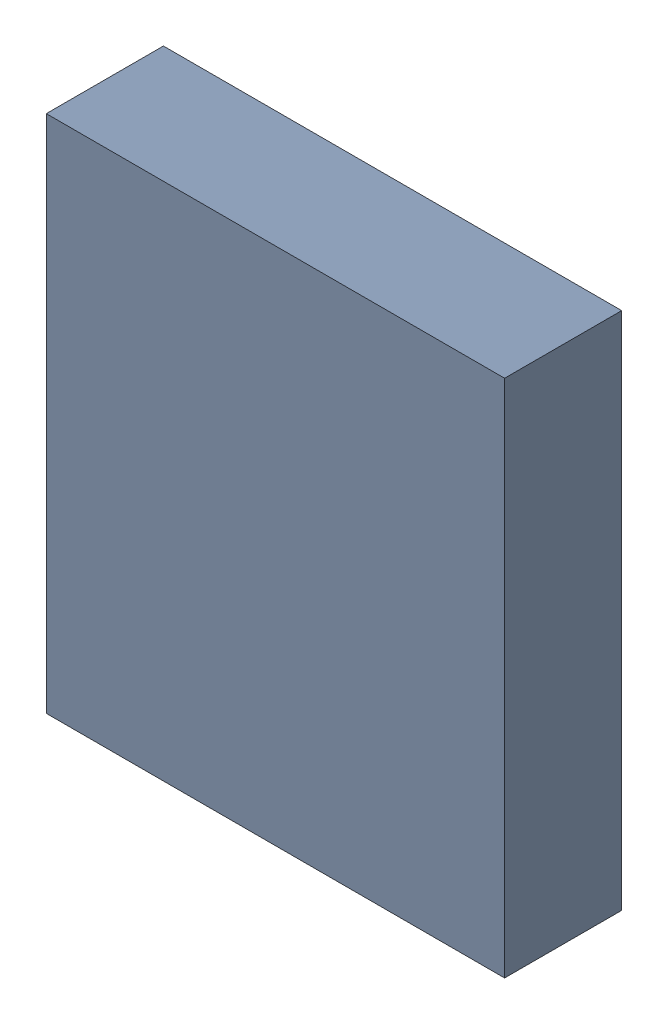
SolidWorks assembly U500_2PCB, configuration Default. Lengths in mm.
Overall size (4.5 5.1 1.15).
2 component instances, 1 part files, 0 mates.
Components (placement in the parent):
- 846483832-1: 846483832 [Default] at (151.5 89 0.05) size (4.5 5.1 1.15)
  - Extruded_18-1: Extruded_18 [Default] at origin size (4.5 5.1 1.15)
